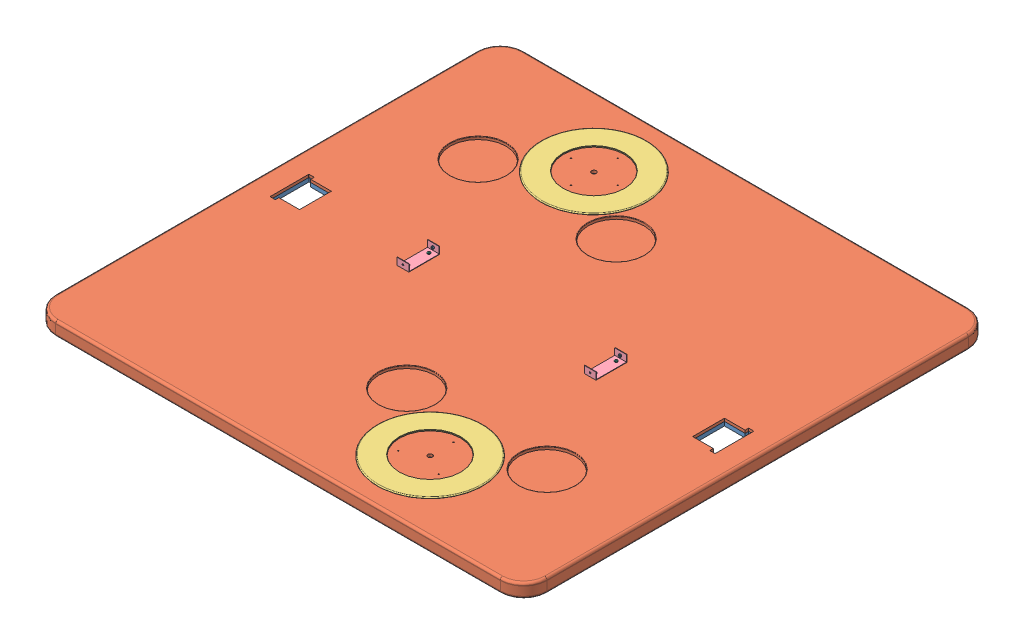
SolidWorks assembly tableTop, configuration Default. Lengths in mm.
Overall size (2100 90 2000).
14 component instances, 6 part files, 12 mates.
Components (placement in the parent):
- table-woodBorar-1: table-woodBorar [Default] at origin size (2072 17 1972)
- table-shell-1: table-shell [Default] at origin size (2100 60 2000)
- table-decorRing-2: table-decorRing [Default] at (-700 0 -1400) size (450 5 450)
- table-decorRing-1: table-decorRing [Default] at origin size (450 5 450)
- table-fix-1: table-fix [Default] at origin size (50 30 132)
- GB_FASTENER_NUT_SNAB1 M6-C-1: GB_FASTENER_NUT_SNAB1 M6-C [GB_FASTENER_NUT_SNAB1 M6-C] at (400 15 58.8) x (-1 0 0) z (0 0 -1) size (11.55 10 5.2)
- GB_FASTENER_NUT_SNAB1 M6-C-2: GB_FASTENER_NUT_SNAB1 M6-C [GB_FASTENER_NUT_SNAB1 M6-C] at (400 15 -64.0012) x (-1 0 0) z (0 0 -1) size (11.55 10 5.2)
- GB_CROSS_SCREWS_TYPE1 M6X10-10  H type-N-1: GB_CROSS_SCREWS_TYPE1 M6X10-10  H type-N [GB_CROSS_SCREWS_TYPE1 M6X10-10  H type-N] at (400 6.6 -45) x (0 -1 0) z (0 0 1) size (14.56 12 12)
- GB_CROSS_SCREWS_TYPE1 M6X10-10  H type-N-2: GB_CROSS_SCREWS_TYPE1 M6X10-10  H type-N [GB_CROSS_SCREWS_TYPE1 M6X10-10  H type-N] at (400 6.6 45) x (0 -1 0) z (0 0 1) size (14.56 12 12)
- table-fix-2: table-fix [Default] x (-1 0 0) z (0 0 -1) size (50 30 132)
- GB_FASTENER_NUT_SNAB1 M6-C-3: GB_FASTENER_NUT_SNAB1 M6-C [GB_FASTENER_NUT_SNAB1 M6-C] at (-400 15 -58.8) size (11.55 10 5.2)
- GB_CROSS_SCREWS_TYPE1 M6X10-10  H type-N-3: GB_CROSS_SCREWS_TYPE1 M6X10-10  H type-N [GB_CROSS_SCREWS_TYPE1 M6X10-10  H type-N] at (-400 6.6 -45) x (0 -1 0) z (0 0 -1) size (14.56 12 12)
- GB_CROSS_SCREWS_TYPE1 M6X10-10  H type-N-4: GB_CROSS_SCREWS_TYPE1 M6X10-10  H type-N [GB_CROSS_SCREWS_TYPE1 M6X10-10  H type-N] at (-400 6.6 45) x (0 -1 0) z (0 0 -1) size (14.56 12 12)
- GB_FASTENER_NUT_SNAB1 M6-C-4: GB_FASTENER_NUT_SNAB1 M6-C [GB_FASTENER_NUT_SNAB1 M6-C] at (-400 15 64.0012) size (11.55 10 5.2)
Mates (geometry in assembly coordinates):
- 重合10: coincident anti-aligned: plane of table-shell-1 through (0 0 0) normal (0 1 0); plane of table-fix-1 through (425 0 66) normal (0 -1 0)
- 同心3: concentric aligned: cylinder of table-shell-1 through (400 0 45) axis (0 1 0) radius 2.5; cylinder of table-fix-1 through (400 2 45) axis (0 1 0) radius 3.5
- 同心16: concentric anti-aligned: cylinder of table-fix-1 through (400 15 66) axis (0 0 1) radius 3.5; cone of GB_FASTENER_NUT_SNAB1 M6-C-1 through (400 15 64) axis (0 0 -1)
- 重合23: coincident anti-aligned: plane of table-fix-1 through (425 0 64) normal (0 0 -1); plane of GB_FASTENER_NUT_SNAB1 M6-C-1 through (400 5 64) normal (0 0 1)
- 同心232: concentric anti-aligned: cylinder of table-shell-1 through (350 -50 700) axis (0 1 0) radius 10; cylinder of table-decorRing-1 through (350 5 700) axis (0 -1 0) radius 130.5
- 重合702: coincident anti-aligned: plane of table-shell-1 through (0 0 0) normal (0 1 0); plane of table-decorRing-1 through (350 0 700) normal (0 -1 0)
- 重合703: coincident anti-aligned: plane of table-shell-1 through (0 0 0) normal (0 1 0); plane of table-decorRing-2 through (-350 0 -700) normal (0 -1 0)
- 同心233: concentric anti-aligned: cylinder of table-shell-1 through (-350 0 -700) axis (0 1 0) radius 10; cylinder of table-decorRing-2 through (-350 5 -700) axis (0 -1 0) radius 130.5
- 同心2341: concentric anti-aligned: cylinder of table-fix-1 through (400 2 -45) axis (0 1 0) radius 3.5; cylinder of GB_CROSS_SCREWS_TYPE1 M6X10-10  H type-N-1 through (400 2.0842 -45) axis (0 -1 0) radius 6
- 重合7041: coincident anti-aligned: plane of table-fix-1 through (425 2 66) normal (0 1 0); plane of GB_CROSS_SCREWS_TYPE1 M6X10-10  H type-N-1 through (403.4 2 -45) normal (0 -1 0)
- 同心2351: concentric anti-aligned: cylinder of table-fix-1 through (400 2 45) axis (0 1 0) radius 3.5; cylinder of GB_CROSS_SCREWS_TYPE1 M6X10-10  H type-N-2 through (400 2.0842 45) axis (0 -1 0) radius 6
- 重合7051: coincident anti-aligned: plane of table-fix-1 through (425 2 66) normal (0 1 0); plane of GB_CROSS_SCREWS_TYPE1 M6X10-10  H type-N-2 through (403.4 2 45) normal (0 -1 0)
